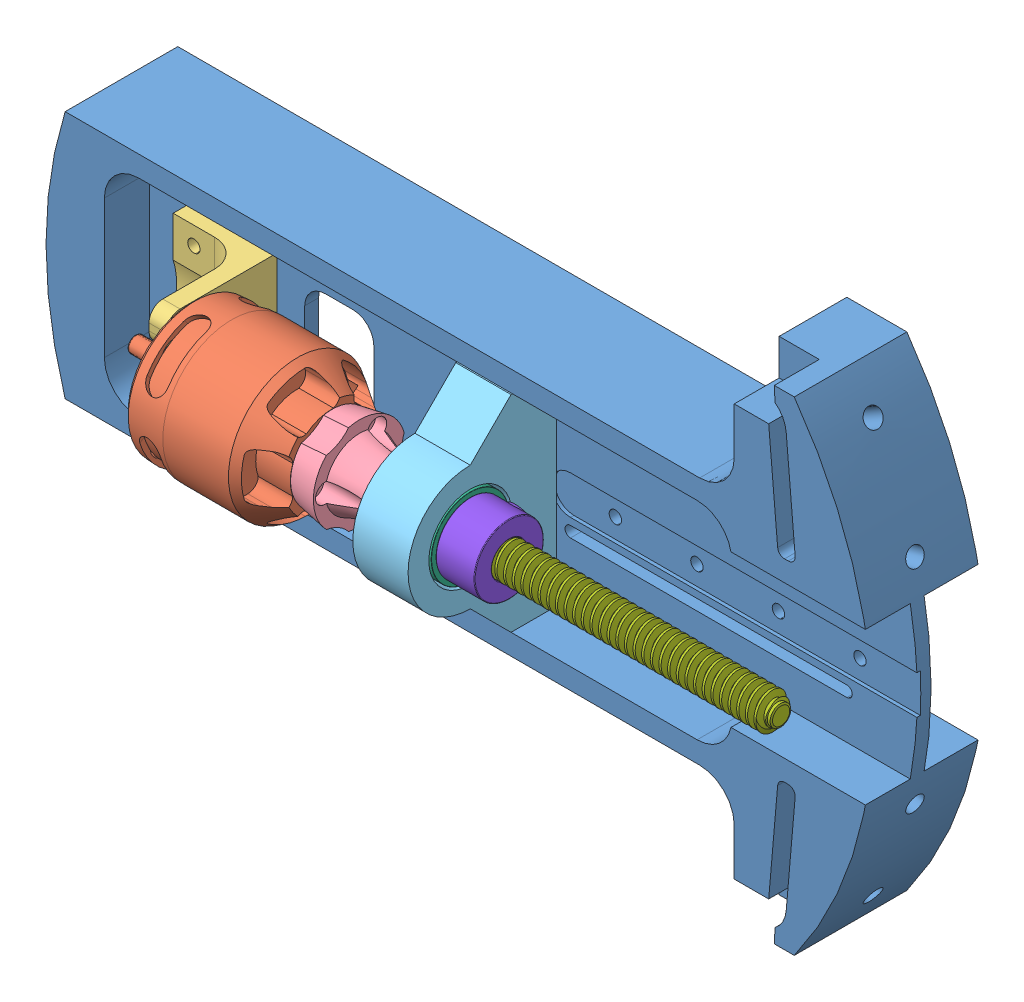
SolidWorks assembly Rotating_Base, configuration Default. Lengths in mm.
Overall size (151.89 88.9 46.06).
9 component instances, 8 part files, 17 mates.
Components (placement in the parent):
- Baseplate_v5-1: Baseplate_v5 [Default] at (-34.4821 -5.7425 16.6996) size (151.89 88.9 20.7)
- med_motor-1: med_motor [Default] at (-56.5801 -5.7425 35.1146) x (0 -0.587936 0.808907) z (-1 0 0) size (25.4 25.4 36.83)
- motor mount-1: motor mount [Default] at (-79.4401 -5.6427 29.3996) x (0 0 1) z (0 1 0) size (20.32 15.88 22.86)
- slip_yoke-1: slip_yoke [Default] at (-50.2301 -5.7425 35.1146) x (0 -1 -0.000818) z (0 -0.000818 1) size (17.03 15.24 16.7)
- Journal_2-1: Journal_2 [Default] at (-24.8301 -5.7425 19.2396) x (0 -1 0) z (-1 0 0) size (37.85 27.3 10.16)
- thrust bearing-1: thrust bearing [6655K13] at (-32.539 -5.7425 35.1146) x (0 1 0) z (0 0 1) size (14.29 3.27 14.29)
- thrust bearing-2: thrust bearing [6655K13] at (-27.2812 -5.7425 35.1146) x (0 -0.997588 0.06941) z (0 0.06941 0.997588) size (14.29 3.27 14.29)
- ACME_Screw-1: ACME_Screw [Default] at (-37.6085 -5.7425 35.1146) x (-1 0 0) z (0 -0.851392 -0.52453) size (70.01 6.35 6.51)
- PS_thrust washer-1: PS_thrust washer [9414T6] at (-21.2582 -5.7425 35.1146) x (0 -0.866025 -0.5) z (1 0 0) size (12.7 12.7 7.14)
Mates (geometry in assembly coordinates):
- Coincident5: coincident anti-aligned: plane of Baseplate_v5-1 through (-34.4821 -5.7425 19.2396) normal (0 0 1); plane of Journal_2-1 through (-34.9899 -5.6874 19.2396) normal (0 0 -1)
- Concentric12: concentric anti-aligned: cylinder of Journal_2-1 through (-34.9899 -5.6874 35.1146) axis (0.999985 -0.005429 0) radius 7.62; cylinder of thrust bearing-2 through (-29.7322 -5.7159 35.1146) axis (-0.999985 0.005429 0) radius 7.1437
- Coincident8: coincident aligned: plane of Journal_2-1 through (-34.9899 -5.6874 35.1146) normal (-0.999985 0.005429 0); plane of thrust bearing-1 through (-34.9899 -5.6874 42.2583) normal (-0.999985 0.005429 0)
- Concentric13: concentric aligned: cylinder of Journal_2-1 through (-34.9899 -5.6874 35.1146) axis (0.999985 -0.005429 0) radius 7.62; cylinder of thrust bearing-1 through (-30.0878 -5.714 35.1146) axis (0.999985 -0.005429 0) radius 7.1437
- Coincident9: coincident aligned: plane of Journal_2-1 through (-24.8301 -5.7425 35.1146) normal (0.999985 -0.005429 0); plane of thrust bearing-2 through (-24.8274 -5.2467 42.2411) normal (0.999985 -0.005429 0)
- Concentric14: concentric aligned: cylinder of thrust bearing-2 through (-29.7322 -5.7159 35.1146) axis (-0.999985 0.005429 0) radius 3.175; cylinder of ACME_Screw-1 through (-50.3342 -5.6041 35.1146) axis (-0.999985 0.005429 0) radius 1.5875
- Concentric25: concentric anti-aligned: cylinder of Journal_2-1 through (-34.9899 -5.6874 35.1146) axis (0.999985 -0.005429 0) radius 11.43; cylinder of PS_thrust washer-1 through (-17.6864 -5.7813 35.1146) axis (-0.999985 0.005429 0) radius 3.175
- Coincident18: coincident anti-aligned: plane of thrust bearing-2 through (-24.8274 -5.2467 42.2411) normal (0.999985 -0.005429 0); plane of PS_thrust washer-1 through (-24.8301 -5.7425 35.1146) normal (-0.999985 0.005429 0)
- Concentric35: concentric anti-aligned: cylinder of slip_yoke-1 through (-46.4197 -5.6253 35.1146) axis (0.999985 -0.005429 0) radius 1.5875; cylinder of ACME_Screw-1 through (-50.3342 -5.6041 35.1146) axis (-0.999985 0.005429 0) radius 1.5875
- Coincident38: coincident anti-aligned: plane of slip_yoke-1 through (-34.9899 -5.6874 35.1146) normal (0.999985 -0.005429 0); plane of Journal_2-1 through (-34.9899 -5.6874 35.1146) normal (-0.999985 0.005429 0)
- Coincident39: coincident anti-aligned: plane of med_motor-1; plane of slip_yoke-1
- Concentric37: concentric anti-aligned: cylinder of med_motor-1 through (-71.228 -13.5189 36.3846) axis (-0.999985 0.005429 0) radius 1.5875; cylinder of motor mount-1 through (-92.1827 -13.4052 36.3846) axis (0.999985 -0.005429 0) radius 1.7018
- Coincident45: coincident: moEndPointRef_w of ?
- Concentric39: concentric aligned: cylinder of med_motor-1 through (-68.6444 -5.5047 35.1146) axis (0.999985 -0.005429 0) radius 12.7; cylinder of Journal_2-1 through (-34.9899 -5.6874 35.1146) axis (0.999985 -0.005429 0) radius 11.43
- Coincident49: coincident anti-aligned: plane of Baseplate_v5-1 through (-34.4821 -5.7425 19.2396) normal (0 0 1); plane of motor mount-1 through (-76.2017 6.0664 19.2396) normal (0 0 -1)
- Coincident50: coincident anti-aligned: plane of med_motor-1; plane of motor mount-1 through (-76.2638 -5.3635 29.3996) normal (0.999985 -0.005429 0)
- Parallel1: parallel anti-aligned: plane of Baseplate_v5-1 through (16.0639 13.3075 -106.3746) normal (0 -1 0); plane of motor mount-1 through (-76.2651 5.7873 19.2396) normal (0 1 0)
